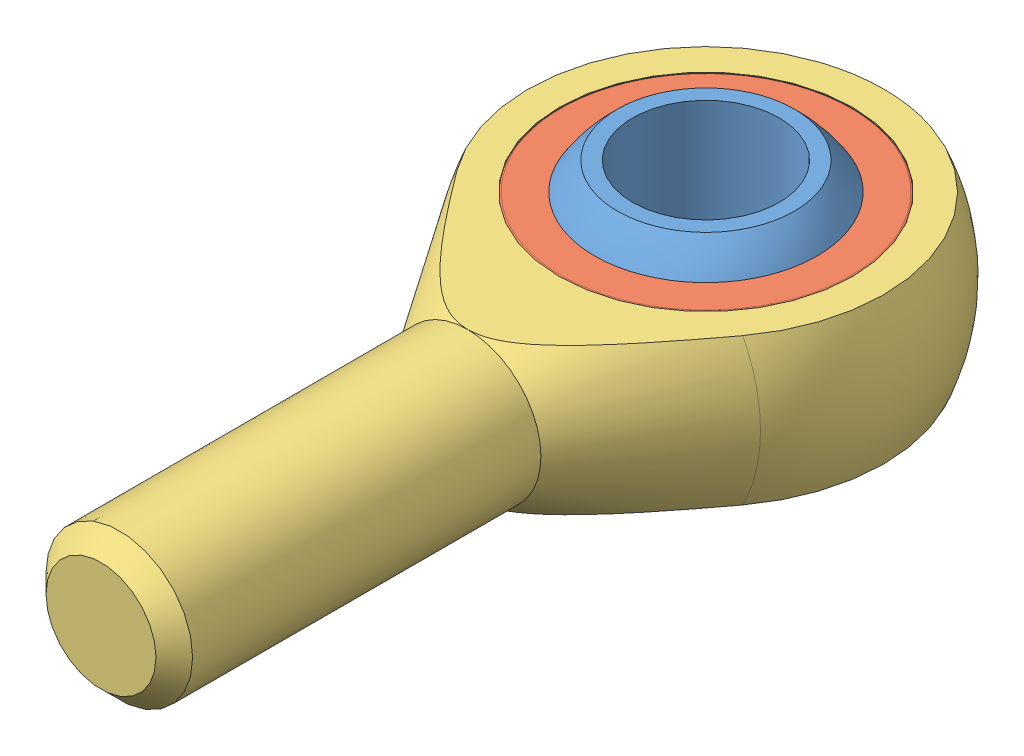
SolidWorks assembly Przegub kulowy_GN 648.2_16, configuration Domyślna. Lengths in mm.
Overall size (42 21 87).
3 component instances, 3 part files, 8 mates.
Components (placement in the parent):
- ROD-END-GN-648.2-1-16-1: ROD-END-GN-648.2-1-16 [16] x (-1 0 0) z (0 0 -1) size (28.52 21 28.52)
- ROD-END-GN-648.2-2-16-1: ROD-END-GN-648.2-2-16 [16] x (0.997964 0 0.063787) z (-0.063787 0 0.997964) size (32 15 32)
- ROD-END-GN-648.2-3-16-1: ROD-END-GN-648.2-3-16 [16] at (0 -0.5 0) size (42 16 87)
Mates (geometry in assembly coordinates):
- Koncentryczne1: concentric: sphere of ROD-END-GN-648.2-2-16-1; sphere of ROD-END-GN-648.2-1-16-1
- Limit kąta1: limit planar angle = 0 rad aligned: cylinder of ROD-END-GN-648.2-1-16-1 through (0 -11.1 0) axis (0 -1 0) radius 8
- Limit kąta2: limit planar angle = 0 rad aligned: cylinder of ROD-END-GN-648.2-2-16-1 through (0 7.5 0) axis (0 -1 0) radius 16
- Koncentryczne5: concentric anti-aligned: cylinder of ROD-END-GN-648.2-3-16-1 through (0 -8.5 0) axis (0 1 0) radius 16; cylinder of ROD-END-GN-648.2-2-16-1 through (0 7.5 0) axis (0 -1 0) radius 16
- Wspólnie1: coincident aligned: plane of ROD-END-GN-648.2-3-16-1 through (-21 7.5 26) normal (0 1 0); plane of ROD-END-GN-648.2-2-16-1 through (0 7.5 0) normal (0 1 0)
- Wspólnie2: coincident anti-aligned: plane of ROD-END-GN-648.2-1-16-1 through (0 0 0) normal (0 0 -1)
- Wspólnie3: coincident aligned: plane of ROD-END-GN-648.2-1-16-1 through (0 0 0) normal (0 1 0)
- Wspólnie4: coincident anti-aligned: plane of ROD-END-GN-648.2-1-16-1 through (0 0 0) normal (-1 0 0)
